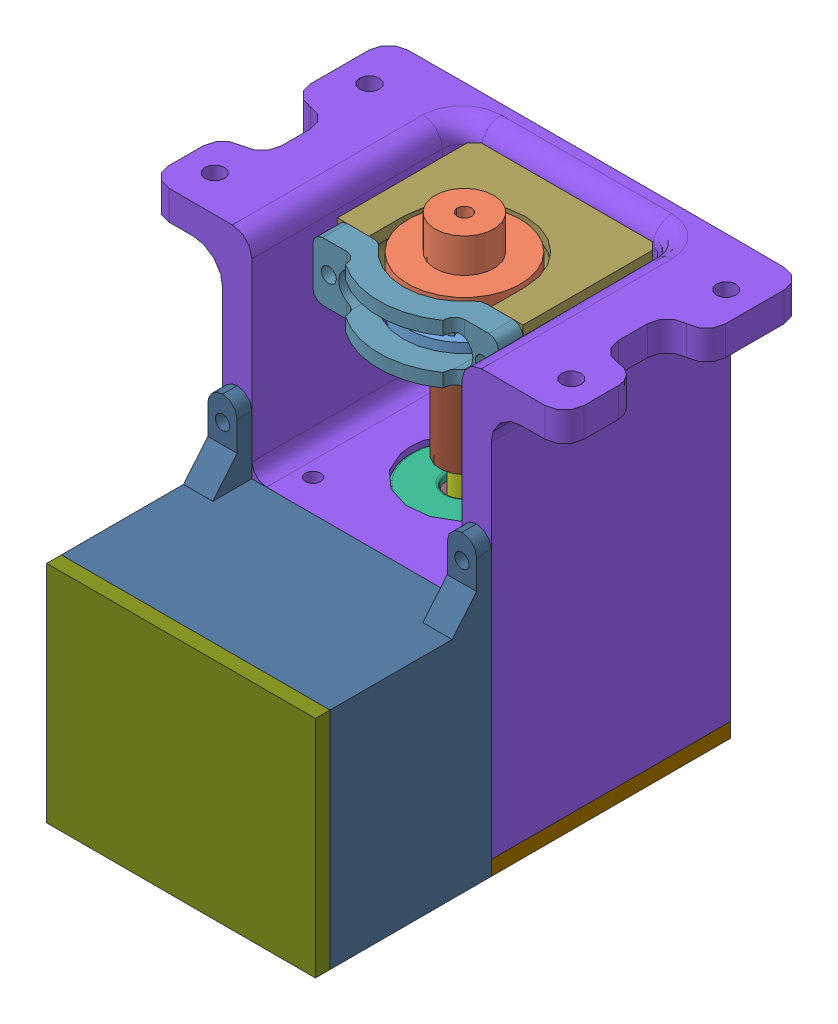
SolidWorks assembly Сборка1, configuration Default. Lengths in mm.
Overall size (85 93 85).
18 component instances, 16 part files, 34 mates.
Components (placement in the parent):
- вращалка.stp-1: вращалка.stp [Default] at (-21.15 32 -22.5165) x (-0.925762 0 -0.378106) z (0.378106 0 -0.925762) size (23 12 23)
- крышка для втулки.stp-1: крышка для втулки.stp [Default] at (-21.15 45 -22.5165) x (0.891011 0 0.453981) z (0.453981 0 -0.891011) size (23 10 23)
- 17HM15-0904S-1: 17HM15-0904S [По умолчанию] at (-21.15 -40 -22.5165) size (42.3 62 42.3)
  - nema17_bottom_40mm-1: nema17_bottom_40mm [По умолчанию] at origin size (42 12 42)
  - radial ball bearing_68_din-1: radial ball bearing_68_din [PreviewCfg] at (0 6.5 0) x (0 -1 0) z (0 0 1) size (8 28 28)
  - nema17_middle_40mm-1: nema17_middle_40mm [По умолчанию] at (0 8.5 0) size (42.3 23.5 42.3)
  - nema17_top_40mm-1: nema17_top_40mm [По умолчанию] at (0 32 0) size (42.3 12.6 42.3)
  - radial ball bearing_68_din-3: radial ball bearing_68_din [PreviewCfg] at (0 36.6 0) x (0 1 0) z (0 0 1) size (8 28 28)
  - nema17_shaft_40mm-1: nema17_shaft_40mm [По умолчанию] at (0 2 0) x (-0.412738 0 0.91085) z (-0.91085 0 -0.412738) size (5 60 5)
- holder-1: holder [Default] at (-21.15 0 -22.0165) x (-1 0 0) z (0 1 0) size (85 52 86)
- Деталь9-1: Деталь9 [Default] at (-21.15 -40 -22.0165) x (1 0 0) z (0 -1 0) size (55 49 3)
- Деталь10-1: Деталь10 [Default] at (-21.15 0 -0.5165) x (-1 0 0) z (0 0 1) size (55 61 33)
- передача момента.stp-5: передача момента.stp [Default] at (-21.15 7 -22.5165) x (0 1 0) z (0.687952 0 -0.725756) size (38 17 17)
- Деталь2-1: Деталь2 [Default] at (-21.15 4 -43.5165) x (-1 0 0) z (0 0 1) size (38 30 28)
- IEC C8 Connector 2 PIN-1: IEC C8 Connector 2 PIN [Default] at (-21.15 -43 31.7835) x (1 0 0) z (0 0 -1) size (22 14 19.2)
- Деталь1-1: Деталь1 [Default] at (-21.15 43 -43.5165) x (1 0 0) z (0 1 0) size (38 10.5 12) (hidden)
- ESP-1: ESP [По умолчанию] at (-9.721 37.2071 -2.5703) x (-1 0 0) z (0 0 1) size (50 26 11)
- rhsrf -1: rhsrf  [Default] at (-21.15 0 32.4835) x (-1 0 0) z (0 0 1) size (55 46 5)
Mates (geometry in assembly coordinates):
- Совпадение1: coincident aligned: plane of 17HM15-0904S-1/nema17_top_40mm-1 through (0 0 -22.5165) normal (1 0 0)
- Совпадение2: coincident aligned: plane of 17HM15-0904S-1/nema17_top_40mm-1 through (-21.15 0 -22.5165) normal (0 1 0)
- Концентричный7: concentric anti-aligned: cylinder of вращалка.stp-1 through (-21.15 40 -22.5165) axis (0 1 0) radius 4.5; cylinder of крышка для втулки.stp-1 through (-21.15 45 -22.5165) axis (0 -1 0) radius 4.5
- Совпадение8: coincident anti-aligned: plane of вращалка.stp-1 through (-21.15 40 -22.5165) normal (0 1 0); plane of крышка для втулки.stp-1 through (-21.15 40 -22.5165) normal (0 -1 0)
- Совпадение12: coincident anti-aligned: plane of 17HM15-0904S-1/nema17_top_40mm-1 through (-21.15 0 -22.5165) normal (0 1 0); plane of держатель-1 through (-21.15 0 -22.0165) normal (0 -1 0)
- Ширина2: width aligned: plane of holder-1 through (-42.65 -40 -22.0165) normal (1 0 0); plane of 17HM15-0904S-1/nema17_bottom_40mm-1 through (0.35 -40 -22.0165) normal (-1 0 0); plane of holder-1 through (-0.15 -31.5 -22.5165) normal (1 0 0); plane of 17HM15-0904S-1/nema17_bottom_40mm-1 through (-42.15 -31.5 -22.5165) normal (-1 0 0)
- Совпадение13: coincident anti-aligned: plane of 17HM15-0904S-1/nema17_bottom_40mm-1 through (-21.15 -31.5 -43.5165) normal (0 0 -1); plane of держатель-1 through (-21.15 -40 -43.5165) normal (0 0 1)
- На месте1: in place: plane of holder-1 through (-21.15 -40 -22.0165) normal (0 -1 0); plane of ? through (0 -40 0) normal (0 -1 0); moOrthogonalPlaneRef_w of holder-1 through (-21.15 -40 -22.0165) normal (0 -1 0); plane of ? through (0 -40 0) normal (0 0 -1); plane of holder-1 through (-21.15 -40 -22.0165) normal (0 -1 0); plane of ? through (0 -40 0) normal (-1 0 0); plane of holder-1 through (-21.15 -40 -22.0165) normal (0 -1 0); unknown of Деталь9-1
- Совпадение14: coincident aligned: plane of assembly through (-21.15 -40 -22.0165) normal (0 -1 0); plane of assembly through (-21.15 -40 -22.0165) normal (0 -1 0)
- Совпадение15: coincident aligned: moOrthogonalPlaneRef_w of держатель-1 through (-21.15 -40 -22.0165) normal (0 0 1); plane of Деталь9^Сборка1-1 through (-21.15 -40 -22.0165) normal (0 0 1)
- Совпадение16: coincident anti-aligned: moOrthogonalPlaneRef_w of держатель-1 through (-21.15 -40 -22.0165) normal (-1 0 0); plane of Деталь9^Сборка1-1 through (-21.15 -40 -22.0165) normal (1 0 0)
- На месте2: in place: plane of holder-1 through (-21.15 3 -0.5165) normal (0 0 1); plane of ? through (0 0 -0.5165) normal (0 0 1); plane of holder-1 through (-21.15 3 -0.5165) normal (0 0 1); plane of ? through (0 0 -0.5165) normal (0 1 0); plane of holder-1 through (-21.15 3 -0.5165) normal (0 0 1); plane of ? through (0 0 -0.5165) normal (1 0 0); plane of holder-1 through (-21.15 3 -0.5165) normal (0 0 1); unknown of Деталь10-1
- Совпадение17: coincident aligned: plane of ?; plane of ?
- Совпадение18: coincident aligned: moOrthogonalPlaneRef_w of держатель-1 through (-21.15 0 -0.5165) normal (0 -1 0); plane of Деталь10-1 through (-21.15 0 -0.5165) normal (0 -1 0)
- Совпадение19: coincident anti-aligned: moOrthogonalPlaneRef_w of держатель-1 through (-21.15 0 -0.5165) normal (1 0 0); plane of Деталь10-1 through (-21.15 0 -0.5165) normal (-1 0 0)
- Совпадение14: coincident anti-aligned: plane of 17HM15-0904S-1/nema17_shaft_40mm-1 through (-21.15 7 -22.5165) normal (0 1 0); plane of передача момента.stp-5 through (-21.15 7 -22.5165) normal (0 -1 0)
- Концентричный8: concentric anti-aligned: cylinder of 17HM15-0904S-1/nema17_shaft_40mm-1 through (-21.15 22 -22.5165) axis (0 -1 0) radius 2.5; cylinder of передача момента.stp-5 through (-21.15 7 -22.5165) axis (0 1 0) radius 5
- Совпадение15: coincident anti-aligned: plane of вращалка.stp-1 through (-21.15 35 -22.5165) normal (0 -1 0); plane of передача момента.stp-5 through (-21.15 35 -22.5165) normal (0 1 0)
- Концентричный9: concentric aligned: cylinder of крышка для втулки.stp-1 through (-21.15 45 -22.5165) axis (0 1 0) radius 6; cylinder of передача момента.stp-5 through (-21.15 7 -22.5165) axis (0 1 0) radius 5
- Ширина3: width aligned: plane of Деталь2-1 through (-40.15 17 -40.5165) normal (-1 0 0); plane of holder-1 through (-2.15 43 -40.5165) normal (1 0 0); plane of Деталь2-1 through (0.35 46 -22.0165) normal (-1 0 0); plane of holder-1 through (-42.65 46 -22.0165) normal (1 0 0)
- Совпадение17: coincident aligned: plane of крышка для втулки.stp-1 through (-21.15 43 -22.5165) normal (0 1 0); plane of Деталь2-1 through (-40.15 43 -40.5165) normal (0 1 0)
- На месте3: in place: plane of ? through (-40.15 43 -40.2826) normal (0 1 0); plane of ? through (0 43 0) normal (0 1 0); plane of ? through (-40.15 43 -40.2826) normal (0 1 0); plane of ? through (0 43 0) normal (0 0 -1); plane of ? through (-40.15 43 -40.2826) normal (0 1 0); plane of ? through (0 43 0) normal (1 0 0); plane of Деталь2-1 through (-40.15 43 -40.5165) normal (0 1 0); unknown of Деталь1-1
- Совпадение18: coincident aligned: plane of ?; plane of ?
- Совпадение19: coincident aligned: moOrthogonalPlaneRef_w of Деталь2-1 through (-21.15 43 -43.5165) normal (0 0 -1); plane of Деталь1-1 through (-21.15 43 -43.5165) normal (0 0 -1)
- Совпадение20: coincident anti-aligned: moOrthogonalPlaneRef_w of Деталь2-1 through (-21.15 43 -43.5165) normal (-1 0 0); plane of Деталь1-1 through (-21.15 43 -43.5165) normal (1 0 0)
- Параллельность1: parallel anti-aligned: plane of Деталь10-1 through (-21.15 0 2.4835) normal (0 0 1); plane of IEC C8 Connector 2 PIN-1 through (-21.15 -43 19.7835) normal (0 0 -1)
- Совпадение22: coincident aligned: plane of Деталь10-1 through (-48.65 -43 2.4835) normal (0 -1 0); plane of IEC C8 Connector 2 PIN-1 through (-21.15 -43 19.7835) normal (0 -1 0)
- Совпадение23: coincident aligned: plane of Деталь10-1 through (-21.15 0 32.4835) normal (0 0 1); plane of IEC C8 Connector 2 PIN-1 through (-21.15 -43 32.4835) normal (0 0 1)
- Ширина4: width anti-aligned: plane of IEC C8 Connector 2 PIN-1 through (-31.9 -39.5 19.7835) normal (-1 0 0); plane of IEC C8 Connector 2 PIN-1 through (-10.4 -39.5 19.7835) normal (1 0 0); plane of Деталь10-1 through (-45.65 -40 32.4835) normal (1 0 0); plane of Деталь10-1 through (3.35 0 32.4835) normal (-1 0 0)
- На месте4: in place: plane of Деталь10-1 through (-21.15 0 32.4835) normal (0 0 1); plane of ? through (0 0 32.4835) normal (0 0 1); plane of Деталь10-1 through (-21.15 0 32.4835) normal (0 0 1); plane of ? through (0 0 32.4835) normal (0 1 0); plane of Деталь10-1 through (-21.15 0 32.4835) normal (0 0 1); plane of ? through (0 0 32.4835) normal (1 0 0); plane of Деталь10-1 through (-21.15 0 32.4835) normal (0 0 1); unknown of rhsrf -1
- Совпадение24: coincident aligned: plane of ?; plane of ?
- Совпадение25: coincident aligned: moOrthogonalPlaneRef_w of Деталь10-1 through (-21.15 0 32.4835) normal (0 -1 0); plane of Деталь1^Сборка1-1 through (-21.15 0 32.4835) normal (0 -1 0)
- Совпадение26: coincident anti-aligned: moOrthogonalPlaneRef_w of Деталь10-1 through (-21.15 0 32.4835) normal (1 0 0); plane of Деталь1^Сборка1-1 through (-21.15 0 32.4835) normal (-1 0 0)
- Совпадение25: coincident anti-aligned: plane of holder-1 through (-21.15 46 -43.5165) normal (0 0 1); plane of Деталь2-1 through (-6.15 17 -43.5165) normal (0 0 -1)
